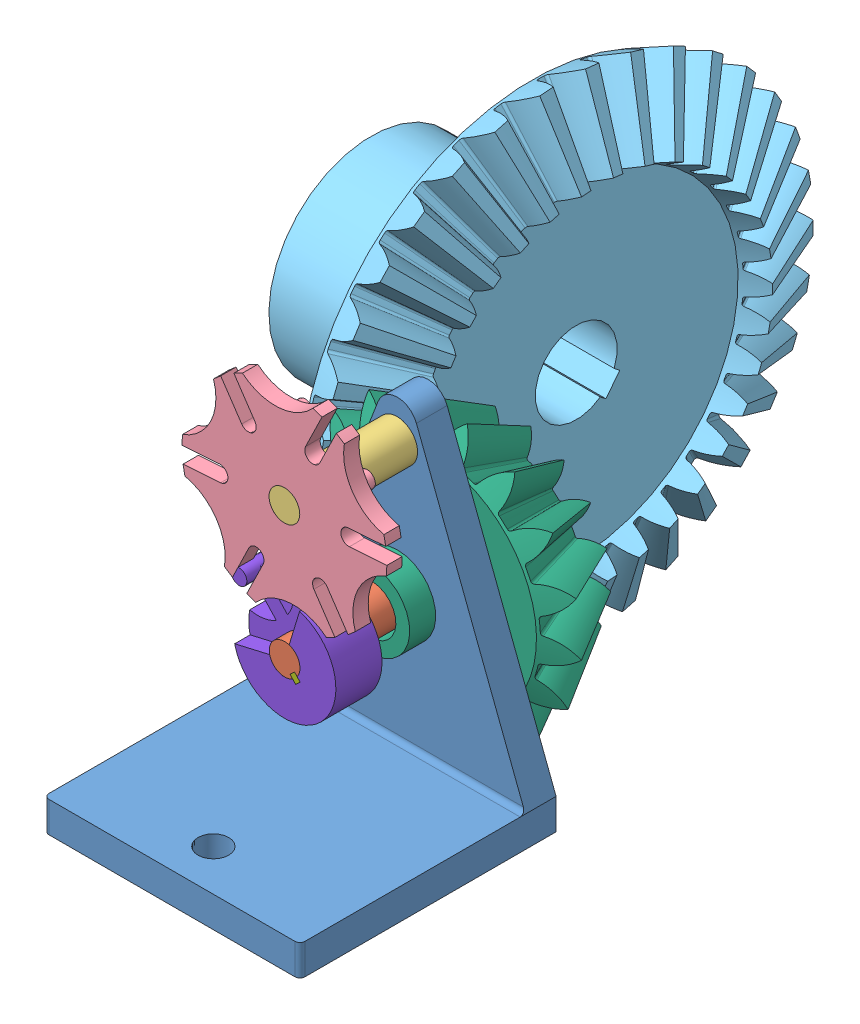
SolidWorks assembly SOLIDEDGE SOLIDWORKS SUBMISSION, configuration Default. Lengths in mm.
Overall size (491.85 680.32 834.68).
8 component instances, 8 part files, 21 mates.
Components (placement in the parent):
- base-1: base [Default] at (-40.8903 0 125) size (250 320 250)
- stift-1: stift [Default] at (-40.8401 153.43 70) x (-0.731193 -0.68217 0) z (-0.68217 0.731193 0) size (40 140 40)
- stift2-1: stift2 [Default] at (-41.0772 283.43 70) x (1 0 0) z (0 1 0) size (40 140 40)
- wheel 1-2: wheel 1 [Default] at (-41.0772 283.43 132.5) x (0.06957 -0.997577 0) z (0.997577 0.06957 0) size (187.69 25 199.4)
- straight bevel gear_iso-2: straight bevel gear_iso [ISO - Straight bevel gear 14M 34GT 17PT 20PA 80FW ---34O200H300MD80.0R1] at (-183.8364 153.43 -244.5981) x (1 0 0) z (0 0.787659 -0.616111) size (225.99 484.15 485.02)
- straight bevel pinion_iso-2: straight bevel pinion_iso [ISO - Straight bevel pinion 14M17PT 34GT 20PA 80FW ---17O75H300MD48.0R1] at (-40.8401 153.43 0) x (0 0 -1) z (0.731193 0.68217 0) size (142.55 269.77 270.92)
- Pin-1: Pin [Default] at (-30.6075 142.4621 95) x (-0.731193 -0.68217 0) z (-0.68217 0.731193 0) size (6 45 8)
- wheel 2-2: wheel 2 [Default] at (-40.8401 153.43 125) x (-0.68217 0.731193 0) z (0.731193 0.68217 0) size (122.5 45 100)
Mates (geometry in assembly coordinates):
- Coincident1: coincident anti-aligned: plane of base-1 through (384.8563 0 250) normal (0 -1 0)
- Coincident2: coincident anti-aligned: plane of base-1 through (134.8563 30 0) normal (0 0 -1)
- Concentric2: concentric anti-aligned: cylinder of base-1 through (259.6694 283.43 0) axis (0 0 1) radius 15; cylinder of stift2-1 through (259.6694 283.43 140) axis (0 0 -1) radius 15
- Coincident3: coincident anti-aligned: plane of base-1 through (259.8563 300 30) normal (0 0 1); plane of stift2-1 through (259.6694 283.43 30) normal (0 0 -1)
- Concentric3: concentric anti-aligned: cylinder of base-1 through (259.9065 153.43 0) axis (0 0 1) radius 15; cylinder of stift-1 through (259.9065 153.43 140) axis (0 0 -1) radius 15
- Coincident4: coincident anti-aligned: plane of base-1 through (259.8563 300 30) normal (0 0 1); plane of stift-1 through (259.9065 153.43 30) normal (0 0 -1)
- Concentric8: concentric anti-aligned: cylinder of stift2-1 through (259.6694 283.43 140) axis (0 0 -1) radius 15; cylinder of wheel 1-2 through (259.6694 283.43 125) axis (0 0 1) radius 15
- Coincident29: coincident anti-aligned: plane of stift2-1 through (259.6694 283.43 125) normal (0 0 1); plane of wheel 1-2 through (259.6694 283.43 125) normal (0 0 -1)
- Coincident6: coincident: point of straight bevel gear_iso-2; point of straight bevel pinion_iso-2
- Perpendicular1: perpendicular: line of straight bevel gear_iso-2 through (106.9102 153.43 -244.5981) axis (1 0 0); line of straight bevel pinion_iso-2 through (259.9065 153.43 0) axis (0 0 -1)
- Parallel3: parallel anti-aligned: plane of straight bevel gear_iso-2 through (-40.0936 153.43 -244.5981) normal (-1 0 0)
- Coincident36: coincident anti-aligned: plane of base-1 through (134.8563 30 0) normal (0 0 -1); plane of straight bevel pinion_iso-2 through (259.9065 153.43 0) normal (0 0 1)
- Concentric13: concentric anti-aligned: cylinder of stift-1 through (259.9065 153.43 110) axis (0 0 -1) radius 20; cylinder of straight bevel pinion_iso-2 through (259.9065 153.43 -300.0001) axis (0 0 1) radius 24
- Coincident38: coincident aligned: plane of stift-1; plane of straight bevel pinion_iso-2
- Coincident44: coincident anti-aligned: unknown of stift-1; unknown of Pin-1
- Coincident49: coincident anti-aligned: plane of stift-1 through (259.9065 153.43 95) normal (0 0 1); plane of Pin-1 through (250.278 164.9317 95) normal (0 0 -1)
- Coincident52: coincident anti-aligned: plane of stift-1 through (259.9065 153.43 95) normal (0 0 1); plane of wheel 2-2 through (259.9065 153.43 95) normal (0 0 -1)
- Coincident53: coincident anti-aligned: plane of stift-1 through (259.9065 153.43 95) normal (0 0 1); plane of wheel 2-2 through (259.9065 153.43 95) normal (0 0 -1)
- Concentric16: concentric aligned: cylinder of stift-1 through (259.9065 153.43 140) axis (0 0 -1) radius 15; cylinder of wheel 2-2 through (259.9065 153.43 140) axis (0 0 -1) radius 15
- Coincident54: coincident anti-aligned: unknown of Pin-1; unknown of wheel 2-2
- Coincident55: coincident anti-aligned: unknown of Pin-1; unknown of wheel 2-2
